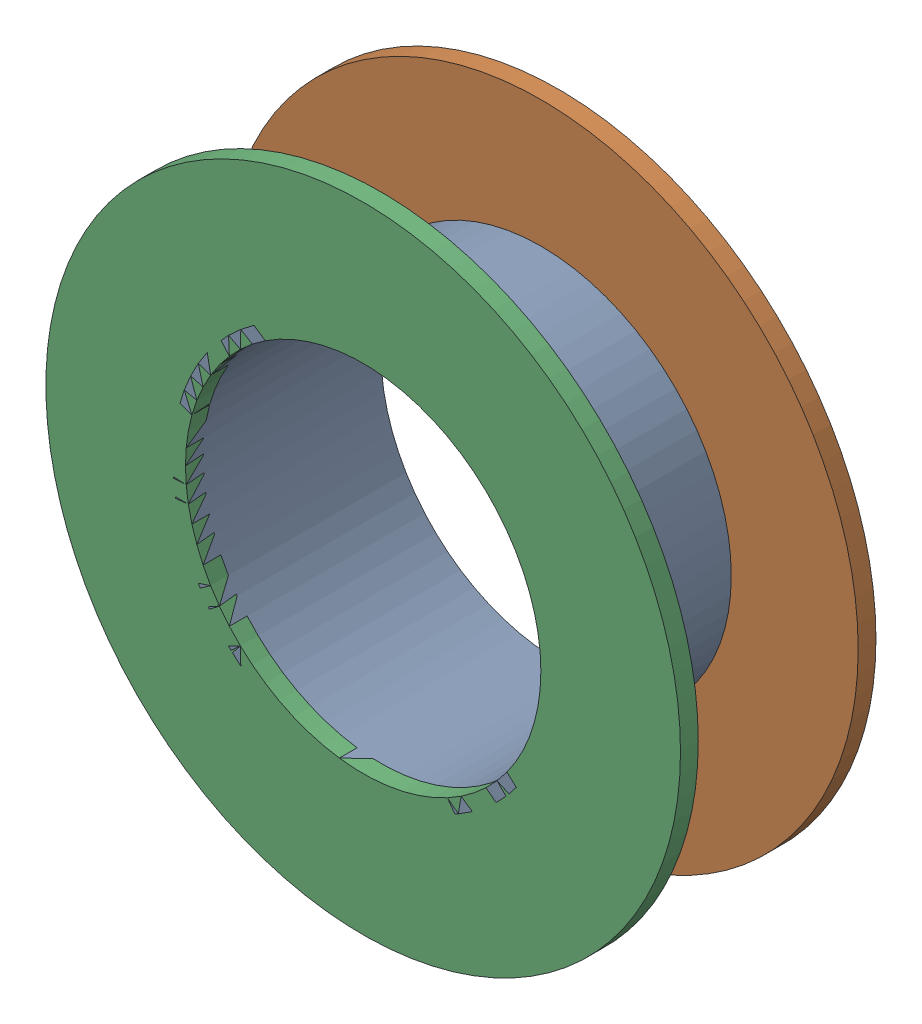
SolidWorks assembly Via (20.3mm,29.4mm) from Top Layer to Bottom Layer, configuration Predeterminado. Lengths in mm.
Overall size (1.27 1.27 0.39).
6 component instances, 2 part files, 0 mates.
Components (placement in the parent):
- Via Hole-1: Via Hole [Predeterminado] at (20.3 29.4 -0.4013) size (0.76 0.76 0.39)
  - Via Hole-Part-1-1: Via Hole-Part-1 [Predeterminado] at origin size (0.76 0.76 0.39)
- Via Top Layer-1: Via Top Layer [Predeterminado] at (20.3 29.4 -0.4013) size (1.27 1.27 0.04)
  - Via Top Layer-Part-1-1: Via Top Layer-Part-1 [Predeterminado] at origin size (1.27 1.27 0.04)
- Via Top Layer-2: Via Top Layer [Predeterminado] at (20.3 29.4 -0.0457) size (1.27 1.27 0.04)
  - Via Top Layer-Part-1-1: Via Top Layer-Part-1 [Predeterminado] at origin size (1.27 1.27 0.04)
